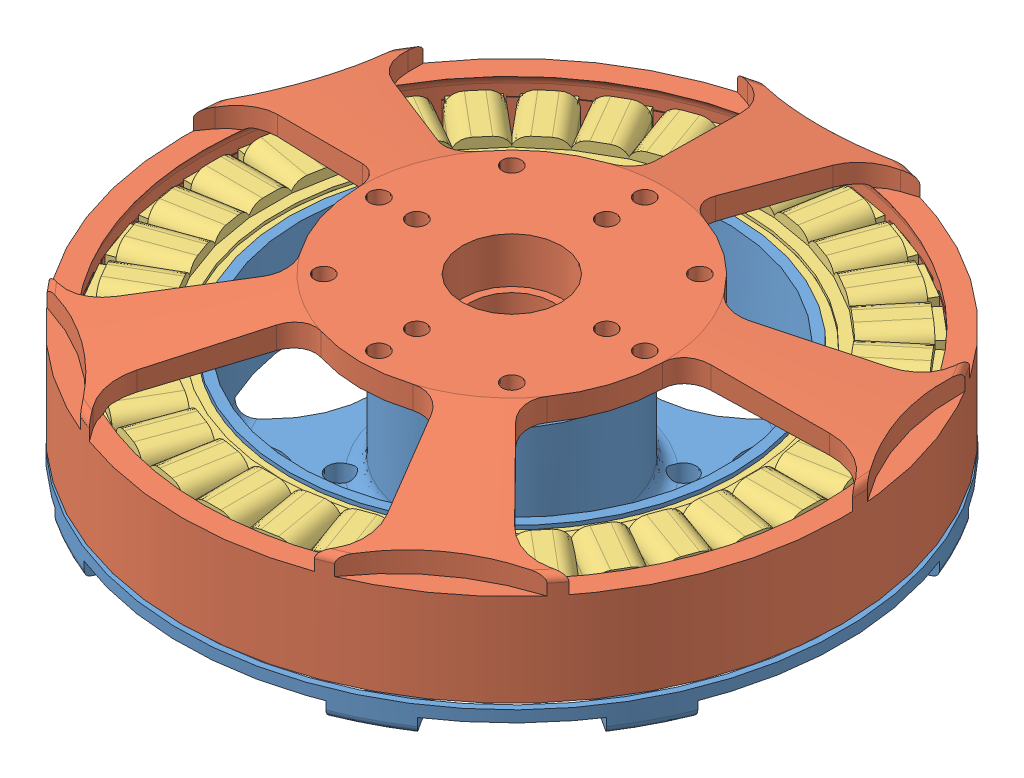
SolidWorks assembly ASM000_TMOTOR_U8, configuration Default. Lengths in mm.
Overall size (88.66 26.69 87.17).
8 component instances, 6 part files, 20 mates.
Components (placement in the parent):
- 020_U8_STATOR_HOUSING-1: 020_U8_STATOR_HOUSING [Default] at origin size (86.8 18.69 86.8)
- 010_U8_ROTOR-1: 010_U8_ROTOR [Default] at origin size (88.66 24.5 87.17)
- 021_U8_STATOR_COILS-1: 021_U8_STATOR_COILS [Default] at (0 -12.5 0) size (81 11.5 81)
- 5972K155_BALL BEARING-1: 5972K155_BALL BEARING [5972K155] at (0 -10.5 0) x (1 0 0) z (0 -1 0) size (24 24 5)
- 5972K155_BALL BEARING-2: 5972K155_BALL BEARING [5972K155] at (0 -22 0) x (1 0 0) z (0 -1 0) size (24 24 5)
- 011_U8_ROTOR_CAP-1: 011_U8_ROTOR_CAP [Default] at (0 -24.5 0) x (1 0 0) z (0 0 -1) size (18.5 2 18.5)
- 91294A128_BLACK ALLOY STEEL FLAT-HEAD SOCKET CAP SCREW-1: 91294A128_BLACK ALLOY STEEL FLAT-HEAD SOCKET CAP SCREW [91294A128] at (0 -26.5 5.5) x (1 0 0) z (0 -1 0) size (6 6 8.29)
- 91294A128_BLACK ALLOY STEEL FLAT-HEAD SOCKET CAP SCREW-2: 91294A128_BLACK ALLOY STEEL FLAT-HEAD SOCKET CAP SCREW [91294A128] at (0 -26.5 -5.5) x (0.999066 0 -0.043219) z (0 -1 0) size (6 6 8.29)
Mates (geometry in assembly coordinates):
- Coincident1: coincident: plane of 010_U8_ROTOR-1 through (0 0 0) normal (0 0 1); plane of assembly through (0 0 0) normal (0 0 1)
- Coincident2: coincident: plane of 010_U8_ROTOR-1 through (0 0 0) normal (0 1 0); plane of assembly through (0 0 0) normal (0 1 0)
- Coincident3: coincident: plane of 010_U8_ROTOR-1 through (0 0 0) normal (1 0 0); plane of assembly through (0 0 0) normal (1 0 0)
- Coincident4: coincident: plane of 020_U8_STATOR_HOUSING-1 through (0 0 0) normal (0 0 1); plane of assembly through (0 0 0) normal (0 0 1)
- Coincident5: coincident: plane of 020_U8_STATOR_HOUSING-1 through (0 0 0) normal (0 1 0); plane of assembly through (0 0 0) normal (0 1 0)
- Coincident6: coincident: plane of 020_U8_STATOR_HOUSING-1 through (0 0 0) normal (1 0 0); plane of assembly through (0 0 0) normal (1 0 0)
- Concentric1: concentric: cylinder of 020_U8_STATOR_HOUSING-1 through (0 0 0) axis (0 1 0) radius 12; cylinder of 5972K155_BALL BEARING-1 through (0 -13 0) axis (0 -1 0) radius 12
- Coincident7: coincident: plane of 010_U8_ROTOR-1 through (8.5 -8 0) normal (0 -1 0); plane of 5972K155_BALL BEARING-1 through (0 -8 7.75) normal (0 1 0)
- Concentric2: concentric: cylinder of 020_U8_STATOR_HOUSING-1 through (0 0 0) axis (0 1 0) radius 12; cylinder of 5972K155_BALL BEARING-2 through (0 -24.5 0) axis (0 -1 0) radius 12
- Coincident8: coincident: plane of 010_U8_ROTOR-1 through (7.5 -24.5 0) normal (0 -1 0); plane of 5972K155_BALL BEARING-2 through (0 -24.5 8.9148) normal (0 -1 0)
- Coincident9: coincident: plane of 010_U8_ROTOR-1 through (7.5 -24.5 0) normal (0 -1 0); plane of 011_U8_ROTOR_CAP-1 through (0 -24.5 0) normal (0 1 0)
- Concentric3: concentric: cylinder of 010_U8_ROTOR-1 through (0 -24.5 5.5) axis (0 -1 0) radius 1.25; cylinder of 011_U8_ROTOR_CAP-1 through (0 -26.5 5.5) axis (0 -1 0) radius 3
- Concentric5: concentric: cylinder of 010_U8_ROTOR-1 through (0 -24.5 -5.5) axis (0 -1 0) radius 1.25; cylinder of 011_U8_ROTOR_CAP-1 through (0 -26.5 -5.5) axis (0 -1 0) radius 3
- Coincident10: coincident: plane of 020_U8_STATOR_HOUSING-1 through (30.45 -16.5 0) normal (0 1 0); plane of 021_U8_STATOR_COILS-1 through (0 -16.5 0) normal (0 -1 0)
- Concentric6: concentric: cylinder of 020_U8_STATOR_HOUSING-1 through (0 0 0) axis (0 1 0) radius 29.25; cylinder of 021_U8_STATOR_COILS-1 through (0 -8.5 0) axis (0 -1 0) radius 29.25
- Coincident11: coincident: plane of 021_U8_STATOR_COILS-1 through (0 -12.5 0) normal (1 0 0); plane of assembly through (0 0 0) normal (1 0 0)
- Concentric7: concentric: cylinder of 010_U8_ROTOR-1 through (0 -24.5 5.5) axis (0 -1 0) radius 1.25; cylinder of 91294A128_BLACK ALLOY STEEL FLAT-HEAD SOCKET CAP SCREW-1 through (0 -26.5 5.5) axis (0 -1 0) radius 3
- Coincident12: coincident: plane of 011_U8_ROTOR_CAP-1 through (0 -26.5 0) normal (0 -1 0); plane of 91294A128_BLACK ALLOY STEEL FLAT-HEAD SOCKET CAP SCREW-1 through (0 -26.5 4) normal (0 -1 0)
- Concentric8: concentric: cylinder of 010_U8_ROTOR-1 through (0 -24.5 -5.5) axis (0 -1 0) radius 1.25; cylinder of 91294A128_BLACK ALLOY STEEL FLAT-HEAD SOCKET CAP SCREW-2 through (0 -26.5 -5.5) axis (0 -1 0) radius 3
- Coincident14: coincident: plane of 011_U8_ROTOR_CAP-1 through (0 -26.5 0) normal (0 -1 0); plane of 91294A128_BLACK ALLOY STEEL FLAT-HEAD SOCKET CAP SCREW-2 through (-0.0648 -26.5 -6.9986) normal (0 -1 0)
